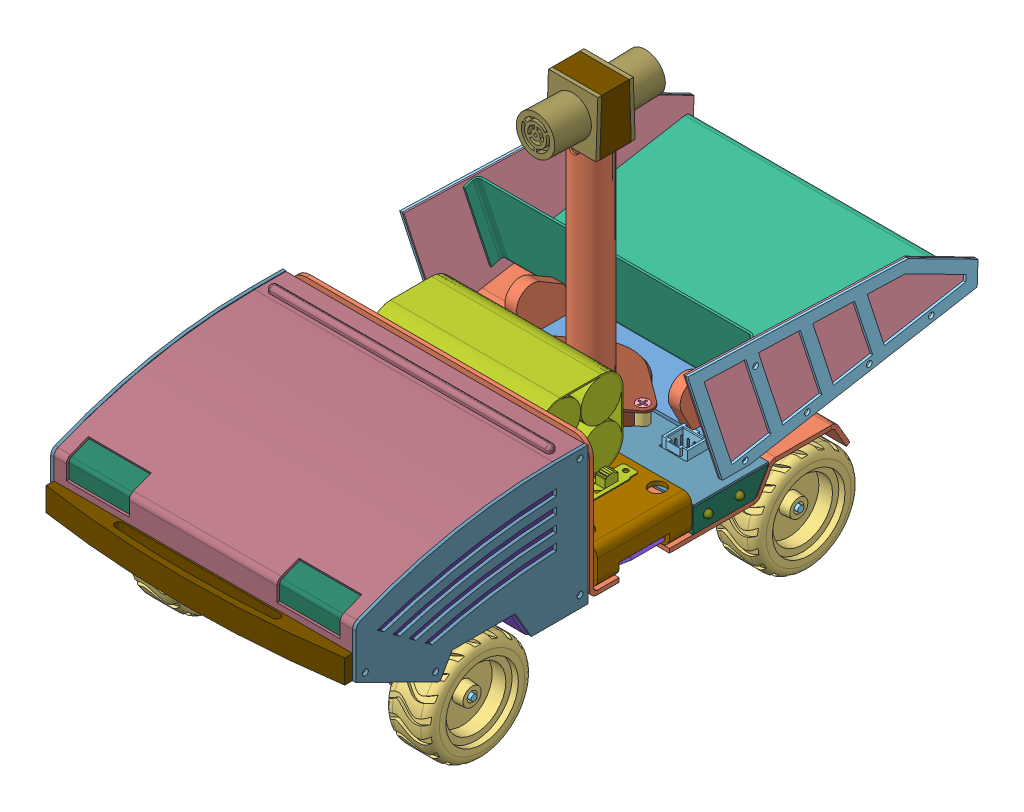
SolidWorks assembly HAULER, TEST ASSEMBLY, configuration Default. Lengths in mm.
Overall size (124.43 158.23 264.06).
96 component instances, 46 part files, 5 mates.
Components (placement in the parent):
- SCOUT, TOP LEVEL-1: SCOUT, TOP LEVEL [Default] at (-66.3 -29.3675 39.5311) size (124.43 158.23 223.86)
  - 6655k13 Thrust Washers-1: 6655k13 Thrust Washers [Default] at (-7.8856 2.7539 2.2902) size (14.15 14.15 4.9)
  - REAR, TOP LEVEL-1: REAR, TOP LEVEL [Default] at (-50.0168 -33.3245 -47.0081) x (-1 0 0) z (0 0 -1) size (124.43 158.23 120.66)
    - PLATE, REAR-1: PLATE, REAR [Default] at (-42.1312 28.0774 12.7174) size (120.65 55.63 120.66)
    - WHEEL ASSEMBLY-1: WHEEL ASSEMBLY [Default-_flexible1] at (7.6153 26.9792 58.7651) x (0 0 1) z (1 0 0) size (42.46 78.6 70.03) (flexible)
      - Pololu 49x19 Wheel-1: Pololu 49x19 Wheel [Default] at (-19.8703 11.8393 2.4418) size (42.46 42.56 19)
      - Pololu Extended Micro Metal Bracket-1: Pololu Extended Micro Metal Bracket [Default] at (-19.8703 6.8393 -18.4366) size (26.6 22.49 26.04)
      - Pololu 298-1 Motor-1: Pololu 298-1 Motor [Default] at (-19.8703 11.8393 -25.1366) x (0 0 -1) z (0 1 0) size (35.87 12 10)
    - WHEEL ASSEMBLY-2: WHEEL ASSEMBLY [Default-_flexible2] at (-91.8778 26.9792 19.0244) x (0 0 -1) z (-1 0 0) size (42.46 78.6 70.03) (flexible)
      - Pololu 49x19 Wheel-1: Pololu 49x19 Wheel [Default] at (-19.8703 11.8393 2.4418) size (42.46 42.56 19)
      - Pololu Extended Micro Metal Bracket-1: Pololu Extended Micro Metal Bracket [Default] at (-19.8703 6.8393 -18.4366) size (26.6 22.49 26.04)
      - Pololu 298-1 Motor-1: Pololu 298-1 Motor [Default] at (-19.8703 11.8393 -25.1366) x (0 0 -1) z (0 1 0) size (35.87 12 10)
    - Socket Head Cap Screw_AI-9: Socket Head Cap Screw_AI [HX-SHCS 0.086-56x0.4375x0.4375-N] at (-77.6912 31.9128 47.8948) x (0 -1 0) z (-0.381305 0 -0.924449) size (13.3 3.56 3.56)
    - Socket Head Cap Screw_AI-10: Socket Head Cap Screw_AI [HX-SHCS 0.086-56x0.4375x0.4375-N] at (-77.6912 31.9128 29.8948) x (0 -1 0) z (0 0 1) size (13.3 3.56 3.56)
    - Socket Head Cap Screw_AI-11: Socket Head Cap Screw_AI [HX-SHCS 0.086-56x0.4375x0.4375-N] at (-6.5712 31.9128 29.8948) x (0 -1 0) z (0 0 1) size (13.3 3.56 3.56)
    - Socket Head Cap Screw_AI-12: Socket Head Cap Screw_AI [HX-SHCS 0.086-56x0.4375x0.4375-N] at (-6.5712 31.9128 47.8948) x (0 -1 0) z (0 0 1) size (13.3 3.56 3.56)
    - 4000mAh 7.4V Battery Pack-1: 4000mAh 7.4V Battery Pack [Default] at (-42.1312 61.2244 -25.7652) x (0 0 -1) z (1 0 0) size (34.29 34.29 68.58)
    - SENSOR, GP2Y0D810-1: SENSOR, GP2Y0D810 [Default] at (9.9271 36.6454 -23.9419) x (0 0 -1) z (0.766044 0.642788 0) size (28.32 10.54 8.89)
    - SENSOR, GP2Y0D810-2: SENSOR, GP2Y0D810 [Default] at (-94.1896 36.6454 -23.9419) x (0 0 -1) z (0.766044 -0.642788 0) size (28.32 10.54 8.89)
    - Battery Support-1: Battery Support [Default] at (-42.1312 29.7284 -26.0192) size (120.65 27.05 38.1)
    - Mounting Block-1: Mounting Block [Default] at (-42.1312 36.0784 -35.6712) x (-1 0 0) z (0 0 -1) size (25.4 12.7 25.4)
    - PF35T-48-1: PF35T-48 [Default] at (-42.1312 31.7284 12.5888) size (50 29.2 35)
    - MaxSonar EZ1-1: MaxSonar EZ1 [Default] at (-42.1312 140.4691 6.6293) x (-1 0 0) z (0 0.034899 -0.999391) size (19.94 22.1 16.38)
    - MaxSonar EZ1-2: MaxSonar EZ1 [Default] at (-42.1312 140.4691 18.5483) x (1 0 0) z (0 0.034899 0.999391) size (19.94 22.1 16.38)
    - BUMPER, REAR-1: BUMPER, REAR [Default] at (-42.1312 29.7284 53.2288) x (-1 0 0) z (0 0 -1) size (80.01 9.53 54.3)
    - PLATE, REAR COVER-1: PLATE, REAR COVER [Default] at (-42.1312 39.2534 72.2788) size (120.65 0.81 81.14)
    - MOUNTING BLOCK, COLOR SENSOR-1: MOUNTING BLOCK, COLOR SENSOR [Default] at (-97.6937 29.7284 5.6038) size (9.53 9.53 30.46)
    - MOUNTING BLOCK, COLOR SENSOR-2: MOUNTING BLOCK, COLOR SENSOR [Default] at (13.4313 29.7284 5.6038) size (9.53 9.53 30.46)
    - SENSOR, COLOR LED-1: SENSOR, COLOR LED [Default] at (-24.0807 23.782 31.9371) x (0 0 -1) z (-0.409692 -0.912224 0) size (5.83 3.66 3.66)
    - SENSOR, COLOR LED-2: SENSOR, COLOR LED [Default] at (-67.3741 22.996 31.9371) x (0 0 -1) z (-0.202984 -0.979182 0) size (5.83 3.66 3.66)
    - COPPER CONTACT-1: COPPER CONTACT [Default] at (-53.2437 34.4909 64.0238) size (15.88 6.35 4.45)
    - COPPER CONTACT-2: COPPER CONTACT [Default] at (-31.0187 34.4909 64.0238) size (15.88 6.35 4.45)
    - MOUNTING BLOCK, SONAR-1: MOUNTING BLOCK, SONAR [Default] at (-42.1312 140.3989 12.5888) x (-1 0 0) z (0 0 -1) size (19.94 22.23 12.7)
    - SHAFT, SONAR MOUNT-1: SHAFT, SONAR MOUNT [Default] at (-42.1312 52.5784 12.5888) x (-0.538443 0 0.842662) z (-0.842662 0 -0.538443) size (4.76 89.41 4.76)
    - SHAFT, SONAR SUPPORT-1: SHAFT, SONAR SUPPORT [Default] at (-42.1312 46.7284 12.5888) x (0.999987 0 0.005105) z (-0.005105 0 0.999987) size (14.22 82.87 14.22)
    - SHAFT, STEPPER SUPPORT-1: SHAFT, STEPPER SUPPORT [Default] at (-63.1312 29.6724 12.5888) size (4.76 16.26 4.76)
    - SHAFT, STEPPER SUPPORT-2: SHAFT, STEPPER SUPPORT [Default] at (-21.1312 29.6724 12.5888) x (0.987866 0 -0.155311) z (0.155311 0 0.987866) size (4.76 16.26 4.76)
    - Flat Head 100 Screw_AI-6: Flat Head 100 Screw_AI [CR-FHM1 0.112-40x0.25x0.25-N] at (-63.1312 46.7284 12.5888) x (0 -1 0) z (0 0 1) size (6.35 4.85 4.85)
    - Flat Head 100 Screw_AI-7: Flat Head 100 Screw_AI [CR-FHM1 0.112-40x0.25x0.25-N] at (-21.1312 46.7284 12.5888) x (0 -1 0) z (0 0 1) size (6.35 4.85 4.85)
    - CONNECTOR, MOLEX 6 PIN-1: CONNECTOR, MOLEX 6 PIN [Default] at (-80.2263 37.7912 12.5433) size (10.34 13.8 9.75)
    - SENSOR, COLOR LED-3: SENSOR, COLOR LED [Default] at (-64.0196 42.7147 3.5765) x (1 0 0) z (0 0.700538 -0.713616) size (5.83 3.66 3.66)
    - SENSOR, COLOR LED-4: SENSOR, COLOR LED [Default] at (-64.0196 42.7147 -9.1235) x (1 0 0) z (0 0.700538 -0.713616) size (5.83 3.66 3.66)
    - SENSOR, COLOR LED-5: SENSOR, COLOR LED [Default] at (-20.2429 42.7147 20.3311) x (-1 0 0) z (0 0.700538 0.713616) size (5.83 3.66 3.66)
    - SENSOR, COLOR LED-6: SENSOR, COLOR LED [Default] at (-20.2429 42.7147 7.6311) x (-1 0 0) z (0 0.700538 0.713616) size (5.83 3.66 3.66)
    - MOUNTING BLOCK, REAR-1: MOUNTING BLOCK, REAR [Default] at (-58.0062 34.4909 31.0038) size (9.53 9.53 28.57)
    - MOUNTING BLOCK, REAR-2: MOUNTING BLOCK, REAR [Default] at (-26.2562 34.4909 31.0038) size (9.53 9.53 28.57)
    - SW3dPS-Sliderswitch-1: SW3dPS-Sliderswitch [Standard] at (-81.1109 44.0794 -21.7288) size (7.4 16 23.2)
  - FRONT, TOP LEVEL-1: FRONT, TOP LEVEL [Default] at (-84.349 -51.7544 28.3431) x (-1 0 0) z (0 0 -1) size (123.38 92.14 123.57)
    - PLATE, FRONT-1: PLATE, FRONT [Default] at (-76.4634 46.5072 -32.0242) size (120.65 12.1 60.8)
    - WHEEL ASSEMBLY-1: WHEEL ASSEMBLY [Default-_flexible3] at (-26.7168 45.4091 2.1802) x (0 0 1) z (1 0 0) size (42.46 78.6 70.03) (flexible)
      - Pololu 49x19 Wheel-1: Pololu 49x19 Wheel [Default] at (-19.8703 11.8393 2.4418) size (42.46 42.56 19)
      - Pololu Extended Micro Metal Bracket-1: Pololu Extended Micro Metal Bracket [Default] at (-19.8703 6.8393 -18.4366) size (26.6 22.49 26.04)
      - Pololu 298-1 Motor-1: Pololu 298-1 Motor [Default] at (-19.8703 11.8393 -25.1366) x (0 0 -1) z (0 1 0) size (35.87 12 10)
    - WHEEL ASSEMBLY-2: WHEEL ASSEMBLY [Default-_flexible4] at (-126.21 45.4091 -37.5605) x (0 0 -1) z (-1 0 0) size (42.46 78.6 70.03) (flexible)
      - Pololu 49x19 Wheel-1: Pololu 49x19 Wheel [Default] at (-19.8703 11.8393 2.4418) size (42.46 42.56 19)
      - Pololu Extended Micro Metal Bracket-1: Pololu Extended Micro Metal Bracket [Default] at (-19.8703 6.8393 -18.4366) size (26.6 22.49 26.04)
      - Pololu 298-1 Motor-1: Pololu 298-1 Motor [Default] at (-19.8703 11.8393 -25.1366) x (0 0 -1) z (0 1 0) size (35.87 12 10)
    - Socket Head Cap Screw_AI-11: Socket Head Cap Screw_AI [HX-SHCS 0.086-56x0.4375x0.4375-N] at (-112.0234 50.3426 -8.6902) x (0 -1 0) z (0.989468 0 0.144748) size (13.3 3.56 3.56)
    - Socket Head Cap Screw_AI-12: Socket Head Cap Screw_AI [HX-SHCS 0.086-56x0.4375x0.4375-N] at (-40.9034 50.3426 -8.6902) x (0 -1 0) z (0.700957 0 0.713204) size (13.3 3.56 3.56)
    - SENSOR, GP2Y0D810-2: SENSOR, GP2Y0D810 [Default] at (-76.7491 52.0249 -21.9932) x (1 0 0) z (0 -0.642788 0.766044) size (28.32 10.54 8.89)
    - BUMPER, FRONT-1: BUMPER, FRONT [Default] at (-76.4634 36.9822 -30.9902) x (-1 0 0) z (0 0 -1) size (69.85 9.53 6.35)
    - Mounting Block-1: Mounting Block [Default] at (-76.4634 54.5082 12.4258) size (25.4 12.7 25.4)
    - Socket Head Shoulder Screw2_AI-2: Socket Head Shoulder Screw2_AI [SHSSCREW 0.25x1.5-N] at (-76.4634 54.5082 2.5706) x (0 0 1) z (-0.728467 -0.685081 0) size (52.4 9.53 9.53)
    - Socket Head Cap Screw_AI-13: Socket Head Cap Screw_AI [HX-SHCS 0.086-56x0.4375x0.4375-N] at (-40.9034 51.2773 -26.6902) x (0 -1 0) z (-0.957829 0 -0.287339) size (13.3 3.56 3.56)
    - Socket Head Cap Screw_AI-14: Socket Head Cap Screw_AI [HX-SHCS 0.086-56x0.4375x0.4375-N] at (-112.0234 51.2773 -26.6902) x (0 -1 0) z (-0.957829 0 -0.287339) size (13.3 3.56 3.56)
    - PCB, MAIN-1: PCB, MAIN [Default] at (-76.4634 67.2082 -21.6044) size (114.3 6.68 88.9)
    - PLATE, FRONT BUMPER-1: PLATE, FRONT BUMPER [Default] at (-76.4634 48.9202 -22.7941) size (120.65 17.91 44.79)
    - COVER, FRONT-1: COVER, FRONT [Default] at (-76.4634 65.9445 25.1258) size (120.65 38.48 93.73)
    - PLATE, FRONT SIDE-1: PLATE, FRONT SIDE [Default] at (-16.1384 46.5072 25.1258) x (0 0 -1) z (1 0 0) size (93.73 55.63 1.27)
    - SW3dPS-USB_mini_B-1: SW3dPS-USB_mini_B [По умолчанию] at (-54.9865 68.8084 -58.5669) x (-1 0 0) z (0 0 -1) (suppressed, hidden)
    - HEADLIGHT COVER, FRONT-1: HEADLIGHT COVER, FRONT [Default] at (-103.1334 74.8345 -67.5842) x (-1 0 0) z (0 0 -1) size (31.75 14.4 11.68)
    - HEADLIGHT COVER, FRONT-2: HEADLIGHT COVER, FRONT [Default] at (-18.0434 74.8345 -67.5842) x (-1 0 0) z (0 0 -1) size (31.75 14.4 11.68)
    - PLATE, FRONT SIDE-2: PLATE, FRONT SIDE [Default] at (-138.0584 46.5072 25.1258) x (0 0 -1) z (1 0 0) size (93.73 55.63 1.27)
    - STRUT, FRONT SIDE-1: STRUT, FRONT SIDE [Default] at (-76.4634 98.9582 21.9508) size (120.65 3.17 6.35)
    - FILTER, FRONT COVER-1: FILTER, FRONT COVER [Default] at (-19.1356 62.8553 14.5951) x (0 0 -1) z (1 0 0) size (76.17 31.33 3)
    - FILTER, FRONT COVER-2: FILTER, FRONT COVER [Default] at (-136.7884 62.8559 13.2551) x (0 0 -1) z (1 0 0) size (76.17 31.33 3)
    - Orb LED-1: Orb LED [Default] at (-118.9744 68.8084 -63.3886) size (6.35 9.53 6.35)
    - Orb LED-2: Orb LED [Default] at (-34.5831 68.8084 -63.3886) size (6.35 9.53 6.35)
  - BUMPER, FRONT SWITCHED-1: BUMPER, FRONT SWITCHED [Default] at (-7.8856 18.9527 98.5308) size (120.65 9.53 7.62)
- HAULER, BASEPLATE TOP LEVEL-1: HAULER, BASEPLATE TOP LEVEL [Default] at (-74.8399 -18.7134 -51.9419) size (85.72 19.05 53.34)
  - HAULER, BASEPLATE, FRAME-1: HAULER, BASEPLATE, FRAME [Default] at (0.6543 -3.9124 26.1611) size (85.72 1.27 48.26)
  - HAULER, BASEPLATE, PIVOT-1: HAULER, BASEPLATE, PIVOT [Default] at (-34.747 8.7876 24.8911) size (4.76 17.78 38.1)
  - HAULER, BASEPLATE, PIVOT-2: HAULER, BASEPLATE, PIVOT [Default] at (31.293 8.7876 24.8911) size (4.76 17.78 38.1)
- HAULER, BUCKET TOP LEVEL-1: HAULER, BUCKET TOP LEVEL [Default] at (-86.0521 12.6426 -81.7675) x (-1 0 0) z (0 -0.034899 -0.999391) size (116.33 70.76 117.78)
  - HAULER, SHAFT, BUCKET STRUT-1: HAULER, SHAFT, BUCKET STRUT [Default] at (-11.2122 -19.1355 18.9169) size (114.3 3.17 3.17)
  - HAULER, SHAFT, BUCKET STRUT-2: HAULER, SHAFT, BUCKET STRUT [Default] at (-11.2122 -24.4165 -5.928) x (1 0 0) z (0 -0.676664 -0.736292) size (114.3 3.17 3.17)
  - HAULER, SHAFT, BUCKET STRUT-3: HAULER, SHAFT, BUCKET STRUT [Default] at (-11.2122 -29.6974 -30.773) x (1 0 0) z (0 -0.33465 -0.942343) size (114.3 3.17 3.17)
  - HAULER, BUCKET, SIDE COVER PLATE-1: HAULER, BUCKET, SIDE COVER PLATE [Default] at (-68.3622 -39.3885 -64.1491) size (0.64 44.45 117.78)
  - HAULER, BUCKET, SIDE COVER PLATE-2: HAULER, BUCKET, SIDE COVER PLATE [Default] at (45.3028 -39.3885 -64.1491) size (0.64 44.45 117.78)
  - HAULER, BUCKET, SIDE PLATE-1: HAULER, BUCKET, SIDE PLATE [Default] at (-70.0132 -39.3885 -64.1491) size (1.02 44.45 117.78)
  - HAULER, BUCKET, SIDE PLATE-2: HAULER, BUCKET, SIDE PLATE [Default] at (45.3028 -39.3885 -64.1491) size (1.02 44.45 117.78)
  - HAULER, BUCKET, BASEPLATE-1: HAULER, BUCKET, BASEPLATE [Default] at (-11.2122 -29.808 -38.9285) x (1 0 0) z (0 0.207912 0.978148) size (113.03 41.34 87.12)
  - TowerPro SG90 Micro Servo-1: TowerPro SG90 Micro Servo [Default] at (-11.2122 -31.6898 -2.6423) x (0 -0.207912 -0.978148) z (0 0.978148 -0.207912) size (32.41 30.61 12.42)
  - TowerPro SG90 Micro Servo Horn Double-1: TowerPro SG90 Micro Servo Horn Double [Single Horn] at (-40.5122 -32.8458 -8.0808) x (0 -0.894254 -0.447559) z (0 0.447559 -0.894254) size (19.62 4.24 7.16)
  - TowerPro SG90 Micro Servo-2: TowerPro SG90 Micro Servo [Default] at (-11.2122 -31.6898 -2.6423) x (0 -0.207912 -0.978148) z (0 -0.978148 0.207912) size (32.41 30.61 12.42)
  - TowerPro SG90 Micro Servo Horn Double-2: TowerPro SG90 Micro Servo Horn Double [Single Horn] at (18.0878 -32.8458 -8.0808) x (0 -0.894254 -0.447559) z (0 -0.447559 0.894254) size (19.62 4.24 7.16)
Mates (geometry in assembly coordinates):
- Coincident1: coincident anti-aligned: plane of SCOUT, TOP LEVEL-1/REAR, TOP LEVEL-1/PLATE, REAR COVER-1 through (-54.4616 -22.6258 -59.447) normal (0 1 0); plane of HAULER, BASEPLATE TOP LEVEL-1/HAULER, BASEPLATE, FRAME-1 through (-118.0006 -22.6258 -74.0408) normal (0 -1 0)
- Concentric1: concentric aligned: cylinder of SCOUT, TOP LEVEL-1/REAR, TOP LEVEL-1/MOUNTING BLOCK, REAR-1 through (-58.3106 -23.4386 -41.6558) axis (0 1 0) radius 1.4224; cylinder of HAULER, BASEPLATE TOP LEVEL-1/HAULER, BASEPLATE, FRAME-1 through (-58.3106 -22.6258 -41.6558) axis (0 1 0) radius 2.1082
- Coincident2: coincident anti-aligned: plane of HAULER, BASEPLATE TOP LEVEL-1 through (-74.8399 -18.7134 -51.9419) normal (1 0 0); plane of HAULER, BUCKET TOP LEVEL-1/HAULER, SHAFT, BUCKET STRUT-1
- Parallel1: parallel aligned: plane of SCOUT, TOP LEVEL-1/REAR, TOP LEVEL-1/MOUNTING BLOCK, COLOR SENSOR-1 through (-13.8606 -23.4386 -25.1458) normal (1 0 0); plane of HAULER, BUCKET TOP LEVEL-1/HAULER, BUCKET, SIDE COVER PLATE-1 through (-17.6899 16.394 -119.3723) normal (1 0 0)
- Angle1: planar angle = 6.108652 rad aligned: plane of HAULER, BUCKET TOP LEVEL-1/HAULER, BUCKET, BASEPLATE-1 through (-131.3549 -15.0382 -41.6901) normal (0 0.984808 0.173648); plane of SCOUT, TOP LEVEL-1/REAR, TOP LEVEL-1/PLATE, REAR COVER-1 through (-54.4616 -22.6258 -59.447) normal (0 1 0)
